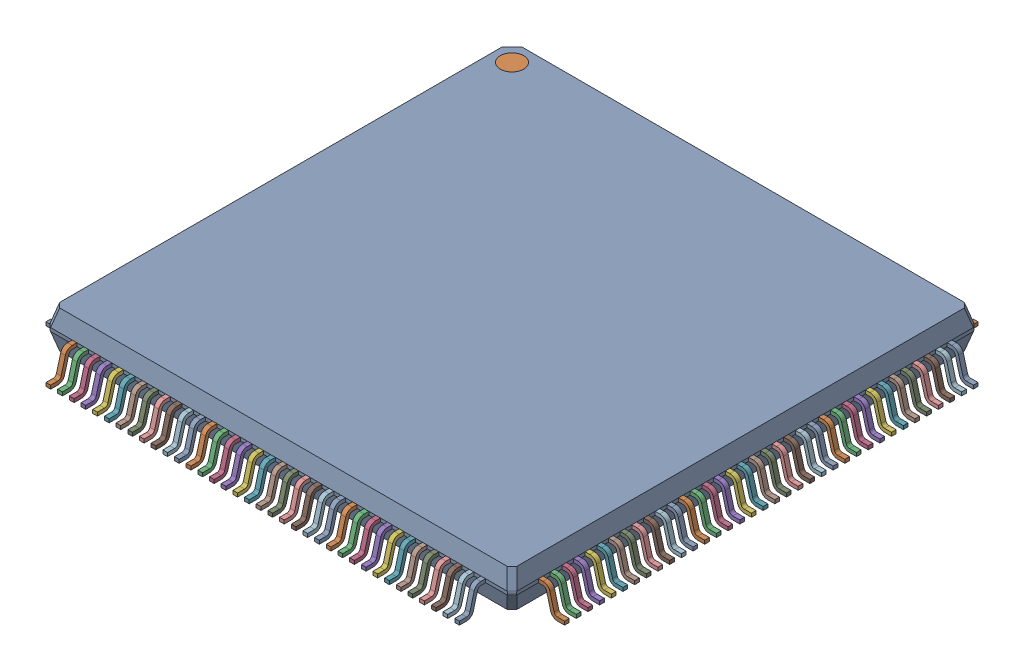
SolidWorks assembly User Library-LQFP144-3, configuration ﾃﾞﾌｫﾙﾄ. Lengths in mm.
Overall size (22.2 1.89 22.2).
146 component instances, 3 part files, 0 mates.
Components (placement in the parent):
- case-1: case [ﾃﾞﾌｫﾙﾄ] at (0 1 0) size (19.96 1.6 19.96)
- pin-28-1: pin-28 [ﾃﾞﾌｫﾙﾄ] at (-8.75 0.9224 9.9806) size (0.2 1.16 1.12)
- pin-28-2: pin-28 [ﾃﾞﾌｫﾙﾄ] at (-8.25 0.9224 9.9806) size (0.2 1.16 1.12)
- pin-28-3: pin-28 [ﾃﾞﾌｫﾙﾄ] at (-7.75 0.9224 9.9806) size (0.2 1.16 1.12)
- pin-28-4: pin-28 [ﾃﾞﾌｫﾙﾄ] at (-7.25 0.9224 9.9806) size (0.2 1.16 1.12)
- pin-28-5: pin-28 [ﾃﾞﾌｫﾙﾄ] at (-6.75 0.9224 9.9806) size (0.2 1.16 1.12)
- pin-28-6: pin-28 [ﾃﾞﾌｫﾙﾄ] at (-6.25 0.9224 9.9806) size (0.2 1.16 1.12)
- pin-28-7: pin-28 [ﾃﾞﾌｫﾙﾄ] at (-5.75 0.9224 9.9806) size (0.2 1.16 1.12)
- pin-28-8: pin-28 [ﾃﾞﾌｫﾙﾄ] at (-5.25 0.9224 9.9806) size (0.2 1.16 1.12)
- pin-28-9: pin-28 [ﾃﾞﾌｫﾙﾄ] at (-4.75 0.9224 9.9806) size (0.2 1.16 1.12)
- pin-28-10: pin-28 [ﾃﾞﾌｫﾙﾄ] at (-4.25 0.9224 9.9806) size (0.2 1.16 1.12)
- pin-28-11: pin-28 [ﾃﾞﾌｫﾙﾄ] at (-3.75 0.9224 9.9806) size (0.2 1.16 1.12)
- pin-28-12: pin-28 [ﾃﾞﾌｫﾙﾄ] at (-3.25 0.9224 9.9806) size (0.2 1.16 1.12)
- pin-28-13: pin-28 [ﾃﾞﾌｫﾙﾄ] at (-2.75 0.9224 9.9806) size (0.2 1.16 1.12)
- pin-28-14: pin-28 [ﾃﾞﾌｫﾙﾄ] at (-2.25 0.9224 9.9806) size (0.2 1.16 1.12)
- pin-28-15: pin-28 [ﾃﾞﾌｫﾙﾄ] at (-1.75 0.9224 9.9806) size (0.2 1.16 1.12)
- pin-28-16: pin-28 [ﾃﾞﾌｫﾙﾄ] at (-1.25 0.9224 9.9806) size (0.2 1.16 1.12)
- pin-28-17: pin-28 [ﾃﾞﾌｫﾙﾄ] at (-0.75 0.9224 9.9806) size (0.2 1.16 1.12)
- pin-28-18: pin-28 [ﾃﾞﾌｫﾙﾄ] at (-0.25 0.9224 9.9806) size (0.2 1.16 1.12)
- pin-28-19: pin-28 [ﾃﾞﾌｫﾙﾄ] at (0.25 0.9224 9.9806) size (0.2 1.16 1.12)
- pin-28-20: pin-28 [ﾃﾞﾌｫﾙﾄ] at (0.75 0.9224 9.9806) size (0.2 1.16 1.12)
- pin-28-21: pin-28 [ﾃﾞﾌｫﾙﾄ] at (1.25 0.9224 9.9806) size (0.2 1.16 1.12)
- pin-28-22: pin-28 [ﾃﾞﾌｫﾙﾄ] at (1.75 0.9224 9.9806) size (0.2 1.16 1.12)
- pin-28-23: pin-28 [ﾃﾞﾌｫﾙﾄ] at (2.25 0.9224 9.9806) size (0.2 1.16 1.12)
- pin-28-24: pin-28 [ﾃﾞﾌｫﾙﾄ] at (2.75 0.9224 9.9806) size (0.2 1.16 1.12)
- pin-28-25: pin-28 [ﾃﾞﾌｫﾙﾄ] at (3.25 0.9224 9.9806) size (0.2 1.16 1.12)
- pin-28-26: pin-28 [ﾃﾞﾌｫﾙﾄ] at (3.75 0.9224 9.9806) size (0.2 1.16 1.12)
- pin-28-27: pin-28 [ﾃﾞﾌｫﾙﾄ] at (4.25 0.9224 9.9806) size (0.2 1.16 1.12)
- pin-28-28: pin-28 [ﾃﾞﾌｫﾙﾄ] at (4.75 0.9224 9.9806) size (0.2 1.16 1.12)
- pin-28-29: pin-28 [ﾃﾞﾌｫﾙﾄ] at (5.25 0.9224 9.9806) size (0.2 1.16 1.12)
- pin-28-30: pin-28 [ﾃﾞﾌｫﾙﾄ] at (5.75 0.9224 9.9806) size (0.2 1.16 1.12)
- pin-28-31: pin-28 [ﾃﾞﾌｫﾙﾄ] at (6.25 0.9224 9.9806) size (0.2 1.16 1.12)
- pin-28-32: pin-28 [ﾃﾞﾌｫﾙﾄ] at (6.75 0.9224 9.9806) size (0.2 1.16 1.12)
- pin-28-33: pin-28 [ﾃﾞﾌｫﾙﾄ] at (7.25 0.9224 9.9806) size (0.2 1.16 1.12)
- pin-28-34: pin-28 [ﾃﾞﾌｫﾙﾄ] at (7.75 0.9224 9.9806) size (0.2 1.16 1.12)
- pin-28-35: pin-28 [ﾃﾞﾌｫﾙﾄ] at (8.25 0.9224 9.9806) size (0.2 1.16 1.12)
- pin-28-36: pin-28 [ﾃﾞﾌｫﾙﾄ] at (8.75 0.9224 9.9806) size (0.2 1.16 1.12)
- pin-28-37: pin-28 [ﾃﾞﾌｫﾙﾄ] at (9.9806 0.9224 8.75) x (0 0 -1) z (1 0 0) size (0.2 1.16 1.12)
- pin-28-38: pin-28 [ﾃﾞﾌｫﾙﾄ] at (9.9806 0.9224 8.25) x (0 0 -1) z (1 0 0) size (0.2 1.16 1.12)
- pin-28-39: pin-28 [ﾃﾞﾌｫﾙﾄ] at (9.9806 0.9224 7.75) x (0 0 -1) z (1 0 0) size (0.2 1.16 1.12)
- pin-28-40: pin-28 [ﾃﾞﾌｫﾙﾄ] at (9.9806 0.9224 7.25) x (0 0 -1) z (1 0 0) size (0.2 1.16 1.12)
- pin-28-41: pin-28 [ﾃﾞﾌｫﾙﾄ] at (9.9806 0.9224 6.75) x (0 0 -1) z (1 0 0) size (0.2 1.16 1.12)
- pin-28-42: pin-28 [ﾃﾞﾌｫﾙﾄ] at (9.9806 0.9224 6.25) x (0 0 -1) z (1 0 0) size (0.2 1.16 1.12)
- pin-28-43: pin-28 [ﾃﾞﾌｫﾙﾄ] at (9.9806 0.9224 5.75) x (0 0 -1) z (1 0 0) size (0.2 1.16 1.12)
- pin-28-44: pin-28 [ﾃﾞﾌｫﾙﾄ] at (9.9806 0.9224 5.25) x (0 0 -1) z (1 0 0) size (0.2 1.16 1.12)
- pin-28-45: pin-28 [ﾃﾞﾌｫﾙﾄ] at (9.9806 0.9224 4.75) x (0 0 -1) z (1 0 0) size (0.2 1.16 1.12)
- pin-28-46: pin-28 [ﾃﾞﾌｫﾙﾄ] at (9.9806 0.9224 4.25) x (0 0 -1) z (1 0 0) size (0.2 1.16 1.12)
- pin-28-47: pin-28 [ﾃﾞﾌｫﾙﾄ] at (9.9806 0.9224 3.75) x (0 0 -1) z (1 0 0) size (0.2 1.16 1.12)
- pin-28-48: pin-28 [ﾃﾞﾌｫﾙﾄ] at (9.9806 0.9224 3.25) x (0 0 -1) z (1 0 0) size (0.2 1.16 1.12)
- pin-28-49: pin-28 [ﾃﾞﾌｫﾙﾄ] at (9.9806 0.9224 2.75) x (0 0 -1) z (1 0 0) size (0.2 1.16 1.12)
- pin-28-50: pin-28 [ﾃﾞﾌｫﾙﾄ] at (9.9806 0.9224 2.25) x (0 0 -1) z (1 0 0) size (0.2 1.16 1.12)
- pin-28-51: pin-28 [ﾃﾞﾌｫﾙﾄ] at (9.9806 0.9224 1.75) x (0 0 -1) z (1 0 0) size (0.2 1.16 1.12)
- pin-28-52: pin-28 [ﾃﾞﾌｫﾙﾄ] at (9.9806 0.9224 1.25) x (0 0 -1) z (1 0 0) size (0.2 1.16 1.12)
- pin-28-53: pin-28 [ﾃﾞﾌｫﾙﾄ] at (9.9806 0.9224 0.75) x (0 0 -1) z (1 0 0) size (0.2 1.16 1.12)
- pin-28-54: pin-28 [ﾃﾞﾌｫﾙﾄ] at (9.9806 0.9224 0.25) x (0 0 -1) z (1 0 0) size (0.2 1.16 1.12)
- pin-28-55: pin-28 [ﾃﾞﾌｫﾙﾄ] at (9.9806 0.9224 -0.25) x (0 0 -1) z (1 0 0) size (0.2 1.16 1.12)
- pin-28-56: pin-28 [ﾃﾞﾌｫﾙﾄ] at (9.9806 0.9224 -0.75) x (0 0 -1) z (1 0 0) size (0.2 1.16 1.12)
- pin-28-57: pin-28 [ﾃﾞﾌｫﾙﾄ] at (9.9806 0.9224 -1.25) x (0 0 -1) z (1 0 0) size (0.2 1.16 1.12)
- pin-28-58: pin-28 [ﾃﾞﾌｫﾙﾄ] at (9.9806 0.9224 -1.75) x (0 0 -1) z (1 0 0) size (0.2 1.16 1.12)
- pin-28-59: pin-28 [ﾃﾞﾌｫﾙﾄ] at (9.9806 0.9224 -2.25) x (0 0 -1) z (1 0 0) size (0.2 1.16 1.12)
- pin-28-60: pin-28 [ﾃﾞﾌｫﾙﾄ] at (9.9806 0.9224 -2.75) x (0 0 -1) z (1 0 0) size (0.2 1.16 1.12)
- pin-28-61: pin-28 [ﾃﾞﾌｫﾙﾄ] at (9.9806 0.9224 -3.25) x (0 0 -1) z (1 0 0) size (0.2 1.16 1.12)
- pin-28-62: pin-28 [ﾃﾞﾌｫﾙﾄ] at (9.9806 0.9224 -3.75) x (0 0 -1) z (1 0 0) size (0.2 1.16 1.12)
- pin-28-63: pin-28 [ﾃﾞﾌｫﾙﾄ] at (9.9806 0.9224 -4.25) x (0 0 -1) z (1 0 0) size (0.2 1.16 1.12)
- pin-28-64: pin-28 [ﾃﾞﾌｫﾙﾄ] at (9.9806 0.9224 -4.75) x (0 0 -1) z (1 0 0) size (0.2 1.16 1.12)
- pin-28-65: pin-28 [ﾃﾞﾌｫﾙﾄ] at (9.9806 0.9224 -5.25) x (0 0 -1) z (1 0 0) size (0.2 1.16 1.12)
- pin-28-66: pin-28 [ﾃﾞﾌｫﾙﾄ] at (9.9806 0.9224 -5.75) x (0 0 -1) z (1 0 0) size (0.2 1.16 1.12)
- pin-28-67: pin-28 [ﾃﾞﾌｫﾙﾄ] at (9.9806 0.9224 -6.25) x (0 0 -1) z (1 0 0) size (0.2 1.16 1.12)
- pin-28-68: pin-28 [ﾃﾞﾌｫﾙﾄ] at (9.9806 0.9224 -6.75) x (0 0 -1) z (1 0 0) size (0.2 1.16 1.12)
- pin-28-69: pin-28 [ﾃﾞﾌｫﾙﾄ] at (9.9806 0.9224 -7.25) x (0 0 -1) z (1 0 0) size (0.2 1.16 1.12)
- pin-28-70: pin-28 [ﾃﾞﾌｫﾙﾄ] at (9.9806 0.9224 -7.75) x (0 0 -1) z (1 0 0) size (0.2 1.16 1.12)
- pin-28-71: pin-28 [ﾃﾞﾌｫﾙﾄ] at (9.9806 0.9224 -8.25) x (0 0 -1) z (1 0 0) size (0.2 1.16 1.12)
- pin-28-72: pin-28 [ﾃﾞﾌｫﾙﾄ] at (9.9806 0.9224 -8.75) x (0 0 -1) z (1 0 0) size (0.2 1.16 1.12)
- pin-28-73: pin-28 [ﾃﾞﾌｫﾙﾄ] at (8.75 0.9224 -9.9806) x (-1 0 0) z (0 0 -1) size (0.2 1.16 1.12)
- pin-28-74: pin-28 [ﾃﾞﾌｫﾙﾄ] at (8.25 0.9224 -9.9806) x (-1 0 0) z (0 0 -1) size (0.2 1.16 1.12)
- pin-28-75: pin-28 [ﾃﾞﾌｫﾙﾄ] at (7.75 0.9224 -9.9806) x (-1 0 0) z (0 0 -1) size (0.2 1.16 1.12)
- pin-28-76: pin-28 [ﾃﾞﾌｫﾙﾄ] at (7.25 0.9224 -9.9806) x (-1 0 0) z (0 0 -1) size (0.2 1.16 1.12)
- pin-28-77: pin-28 [ﾃﾞﾌｫﾙﾄ] at (6.75 0.9224 -9.9806) x (-1 0 0) z (0 0 -1) size (0.2 1.16 1.12)
- pin-28-78: pin-28 [ﾃﾞﾌｫﾙﾄ] at (6.25 0.9224 -9.9806) x (-1 0 0) z (0 0 -1) size (0.2 1.16 1.12)
- pin-28-79: pin-28 [ﾃﾞﾌｫﾙﾄ] at (5.75 0.9224 -9.9806) x (-1 0 0) z (0 0 -1) size (0.2 1.16 1.12)
- pin-28-80: pin-28 [ﾃﾞﾌｫﾙﾄ] at (5.25 0.9224 -9.9806) x (-1 0 0) z (0 0 -1) size (0.2 1.16 1.12)
- pin-28-81: pin-28 [ﾃﾞﾌｫﾙﾄ] at (4.75 0.9224 -9.9806) x (-1 0 0) z (0 0 -1) size (0.2 1.16 1.12)
- pin-28-82: pin-28 [ﾃﾞﾌｫﾙﾄ] at (4.25 0.9224 -9.9806) x (-1 0 0) z (0 0 -1) size (0.2 1.16 1.12)
- pin-28-83: pin-28 [ﾃﾞﾌｫﾙﾄ] at (3.75 0.9224 -9.9806) x (-1 0 0) z (0 0 -1) size (0.2 1.16 1.12)
- pin-28-84: pin-28 [ﾃﾞﾌｫﾙﾄ] at (3.25 0.9224 -9.9806) x (-1 0 0) z (0 0 -1) size (0.2 1.16 1.12)
- pin-28-85: pin-28 [ﾃﾞﾌｫﾙﾄ] at (2.75 0.9224 -9.9806) x (-1 0 0) z (0 0 -1) size (0.2 1.16 1.12)
- pin-28-86: pin-28 [ﾃﾞﾌｫﾙﾄ] at (2.25 0.9224 -9.9806) x (-1 0 0) z (0 0 -1) size (0.2 1.16 1.12)
- pin-28-87: pin-28 [ﾃﾞﾌｫﾙﾄ] at (1.75 0.9224 -9.9806) x (-1 0 0) z (0 0 -1) size (0.2 1.16 1.12)
- pin-28-88: pin-28 [ﾃﾞﾌｫﾙﾄ] at (1.25 0.9224 -9.9806) x (-1 0 0) z (0 0 -1) size (0.2 1.16 1.12)
- pin-28-89: pin-28 [ﾃﾞﾌｫﾙﾄ] at (0.75 0.9224 -9.9806) x (-1 0 0) z (0 0 -1) size (0.2 1.16 1.12)
- pin-28-90: pin-28 [ﾃﾞﾌｫﾙﾄ] at (0.25 0.9224 -9.9806) x (-1 0 0) z (0 0 -1) size (0.2 1.16 1.12)
- pin-28-91: pin-28 [ﾃﾞﾌｫﾙﾄ] at (-0.25 0.9224 -9.9806) x (-1 0 0) z (0 0 -1) size (0.2 1.16 1.12)
- pin-28-92: pin-28 [ﾃﾞﾌｫﾙﾄ] at (-0.75 0.9224 -9.9806) x (-1 0 0) z (0 0 -1) size (0.2 1.16 1.12)
- pin-28-93: pin-28 [ﾃﾞﾌｫﾙﾄ] at (-1.25 0.9224 -9.9806) x (-1 0 0) z (0 0 -1) size (0.2 1.16 1.12)
- pin-28-94: pin-28 [ﾃﾞﾌｫﾙﾄ] at (-1.75 0.9224 -9.9806) x (-1 0 0) z (0 0 -1) size (0.2 1.16 1.12)
- pin-28-95: pin-28 [ﾃﾞﾌｫﾙﾄ] at (-2.25 0.9224 -9.9806) x (-1 0 0) z (0 0 -1) size (0.2 1.16 1.12)
- pin-28-96: pin-28 [ﾃﾞﾌｫﾙﾄ] at (-2.75 0.9224 -9.9806) x (-1 0 0) z (0 0 -1) size (0.2 1.16 1.12)
- pin-28-97: pin-28 [ﾃﾞﾌｫﾙﾄ] at (-3.25 0.9224 -9.9806) x (-1 0 0) z (0 0 -1) size (0.2 1.16 1.12)
- pin-28-98: pin-28 [ﾃﾞﾌｫﾙﾄ] at (-3.75 0.9224 -9.9806) x (-1 0 0) z (0 0 -1) size (0.2 1.16 1.12)
- pin-28-99: pin-28 [ﾃﾞﾌｫﾙﾄ] at (-4.25 0.9224 -9.9806) x (-1 0 0) z (0 0 -1) size (0.2 1.16 1.12)
- pin-28-100: pin-28 [ﾃﾞﾌｫﾙﾄ] at (-4.75 0.9224 -9.9806) x (-1 0 0) z (0 0 -1) size (0.2 1.16 1.12)
- pin-28-101: pin-28 [ﾃﾞﾌｫﾙﾄ] at (-5.25 0.9224 -9.9806) x (-1 0 0) z (0 0 -1) size (0.2 1.16 1.12)
- pin-28-102: pin-28 [ﾃﾞﾌｫﾙﾄ] at (-5.75 0.9224 -9.9806) x (-1 0 0) z (0 0 -1) size (0.2 1.16 1.12)
- pin-28-103: pin-28 [ﾃﾞﾌｫﾙﾄ] at (-6.25 0.9224 -9.9806) x (-1 0 0) z (0 0 -1) size (0.2 1.16 1.12)
- pin-28-104: pin-28 [ﾃﾞﾌｫﾙﾄ] at (-6.75 0.9224 -9.9806) x (-1 0 0) z (0 0 -1) size (0.2 1.16 1.12)
- pin-28-105: pin-28 [ﾃﾞﾌｫﾙﾄ] at (-7.25 0.9224 -9.9806) x (-1 0 0) z (0 0 -1) size (0.2 1.16 1.12)
- pin-28-106: pin-28 [ﾃﾞﾌｫﾙﾄ] at (-7.75 0.9224 -9.9806) x (-1 0 0) z (0 0 -1) size (0.2 1.16 1.12)
- pin-28-107: pin-28 [ﾃﾞﾌｫﾙﾄ] at (-8.25 0.9224 -9.9806) x (-1 0 0) z (0 0 -1) size (0.2 1.16 1.12)
- pin-28-108: pin-28 [ﾃﾞﾌｫﾙﾄ] at (-8.75 0.9224 -9.9806) x (-1 0 0) z (0 0 -1) size (0.2 1.16 1.12)
- pin-28-109: pin-28 [ﾃﾞﾌｫﾙﾄ] at (-9.9806 0.9224 -8.75) x (0 0 1) z (-1 0 0) size (0.2 1.16 1.12)
- pin-28-110: pin-28 [ﾃﾞﾌｫﾙﾄ] at (-9.9806 0.9224 -8.25) x (0 0 1) z (-1 0 0) size (0.2 1.16 1.12)
- pin-28-111: pin-28 [ﾃﾞﾌｫﾙﾄ] at (-9.9806 0.9224 -7.75) x (0 0 1) z (-1 0 0) size (0.2 1.16 1.12)
- pin-28-112: pin-28 [ﾃﾞﾌｫﾙﾄ] at (-9.9806 0.9224 -7.25) x (0 0 1) z (-1 0 0) size (0.2 1.16 1.12)
- pin-28-113: pin-28 [ﾃﾞﾌｫﾙﾄ] at (-9.9806 0.9224 -6.75) x (0 0 1) z (-1 0 0) size (0.2 1.16 1.12)
- pin-28-114: pin-28 [ﾃﾞﾌｫﾙﾄ] at (-9.9806 0.9224 -6.25) x (0 0 1) z (-1 0 0) size (0.2 1.16 1.12)
- pin-28-115: pin-28 [ﾃﾞﾌｫﾙﾄ] at (-9.9806 0.9224 -5.75) x (0 0 1) z (-1 0 0) size (0.2 1.16 1.12)
- pin-28-116: pin-28 [ﾃﾞﾌｫﾙﾄ] at (-9.9806 0.9224 -5.25) x (0 0 1) z (-1 0 0) size (0.2 1.16 1.12)
- pin-28-117: pin-28 [ﾃﾞﾌｫﾙﾄ] at (-9.9806 0.9224 -4.75) x (0 0 1) z (-1 0 0) size (0.2 1.16 1.12)
- pin-28-118: pin-28 [ﾃﾞﾌｫﾙﾄ] at (-9.9806 0.9224 -4.25) x (0 0 1) z (-1 0 0) size (0.2 1.16 1.12)
- pin-28-119: pin-28 [ﾃﾞﾌｫﾙﾄ] at (-9.9806 0.9224 -3.75) x (0 0 1) z (-1 0 0) size (0.2 1.16 1.12)
- pin-28-120: pin-28 [ﾃﾞﾌｫﾙﾄ] at (-9.9806 0.9224 -3.25) x (0 0 1) z (-1 0 0) size (0.2 1.16 1.12)
- pin-28-121: pin-28 [ﾃﾞﾌｫﾙﾄ] at (-9.9806 0.9224 -2.75) x (0 0 1) z (-1 0 0) size (0.2 1.16 1.12)
- pin-28-122: pin-28 [ﾃﾞﾌｫﾙﾄ] at (-9.9806 0.9224 -2.25) x (0 0 1) z (-1 0 0) size (0.2 1.16 1.12)
- pin-28-123: pin-28 [ﾃﾞﾌｫﾙﾄ] at (-9.9806 0.9224 -1.75) x (0 0 1) z (-1 0 0) size (0.2 1.16 1.12)
- pin-28-124: pin-28 [ﾃﾞﾌｫﾙﾄ] at (-9.9806 0.9224 -1.25) x (0 0 1) z (-1 0 0) size (0.2 1.16 1.12)
- pin-28-125: pin-28 [ﾃﾞﾌｫﾙﾄ] at (-9.9806 0.9224 -0.75) x (0 0 1) z (-1 0 0) size (0.2 1.16 1.12)
- pin-28-126: pin-28 [ﾃﾞﾌｫﾙﾄ] at (-9.9806 0.9224 -0.25) x (0 0 1) z (-1 0 0) size (0.2 1.16 1.12)
- pin-28-127: pin-28 [ﾃﾞﾌｫﾙﾄ] at (-9.9806 0.9224 0.25) x (0 0 1) z (-1 0 0) size (0.2 1.16 1.12)
- pin-28-128: pin-28 [ﾃﾞﾌｫﾙﾄ] at (-9.9806 0.9224 0.75) x (0 0 1) z (-1 0 0) size (0.2 1.16 1.12)
- pin-28-129: pin-28 [ﾃﾞﾌｫﾙﾄ] at (-9.9806 0.9224 1.25) x (0 0 1) z (-1 0 0) size (0.2 1.16 1.12)
- pin-28-130: pin-28 [ﾃﾞﾌｫﾙﾄ] at (-9.9806 0.9224 1.75) x (0 0 1) z (-1 0 0) size (0.2 1.16 1.12)
- pin-28-131: pin-28 [ﾃﾞﾌｫﾙﾄ] at (-9.9806 0.9224 2.25) x (0 0 1) z (-1 0 0) size (0.2 1.16 1.12)
- pin-28-132: pin-28 [ﾃﾞﾌｫﾙﾄ] at (-9.9806 0.9224 2.75) x (0 0 1) z (-1 0 0) size (0.2 1.16 1.12)
- pin-28-133: pin-28 [ﾃﾞﾌｫﾙﾄ] at (-9.9806 0.9224 3.25) x (0 0 1) z (-1 0 0) size (0.2 1.16 1.12)
- pin-28-134: pin-28 [ﾃﾞﾌｫﾙﾄ] at (-9.9806 0.9224 3.75) x (0 0 1) z (-1 0 0) size (0.2 1.16 1.12)
- pin-28-135: pin-28 [ﾃﾞﾌｫﾙﾄ] at (-9.9806 0.9224 4.25) x (0 0 1) z (-1 0 0) size (0.2 1.16 1.12)
- pin-28-136: pin-28 [ﾃﾞﾌｫﾙﾄ] at (-9.9806 0.9224 4.75) x (0 0 1) z (-1 0 0) size (0.2 1.16 1.12)
- pin-28-137: pin-28 [ﾃﾞﾌｫﾙﾄ] at (-9.9806 0.9224 5.25) x (0 0 1) z (-1 0 0) size (0.2 1.16 1.12)
- pin-28-138: pin-28 [ﾃﾞﾌｫﾙﾄ] at (-9.9806 0.9224 5.75) x (0 0 1) z (-1 0 0) size (0.2 1.16 1.12)
- pin-28-139: pin-28 [ﾃﾞﾌｫﾙﾄ] at (-9.9806 0.9224 6.25) x (0 0 1) z (-1 0 0) size (0.2 1.16 1.12)
- pin-28-140: pin-28 [ﾃﾞﾌｫﾙﾄ] at (-9.9806 0.9224 6.75) x (0 0 1) z (-1 0 0) size (0.2 1.16 1.12)
- pin-28-141: pin-28 [ﾃﾞﾌｫﾙﾄ] at (-9.9806 0.9224 7.25) x (0 0 1) z (-1 0 0) size (0.2 1.16 1.12)
- pin-28-142: pin-28 [ﾃﾞﾌｫﾙﾄ] at (-9.9806 0.9224 7.75) x (0 0 1) z (-1 0 0) size (0.2 1.16 1.12)
- pin-28-143: pin-28 [ﾃﾞﾌｫﾙﾄ] at (-9.9806 0.9224 8.25) x (0 0 1) z (-1 0 0) size (0.2 1.16 1.12)
- pin-28-144: pin-28 [ﾃﾞﾌｫﾙﾄ] at (-9.9806 0.9224 8.75) x (0 0 1) z (-1 0 0) size (0.2 1.16 1.12)
- circle-1: circle [ﾃﾞﾌｫﾙﾄ] at (-9 1.7 -9) size (1 0.1 1)
